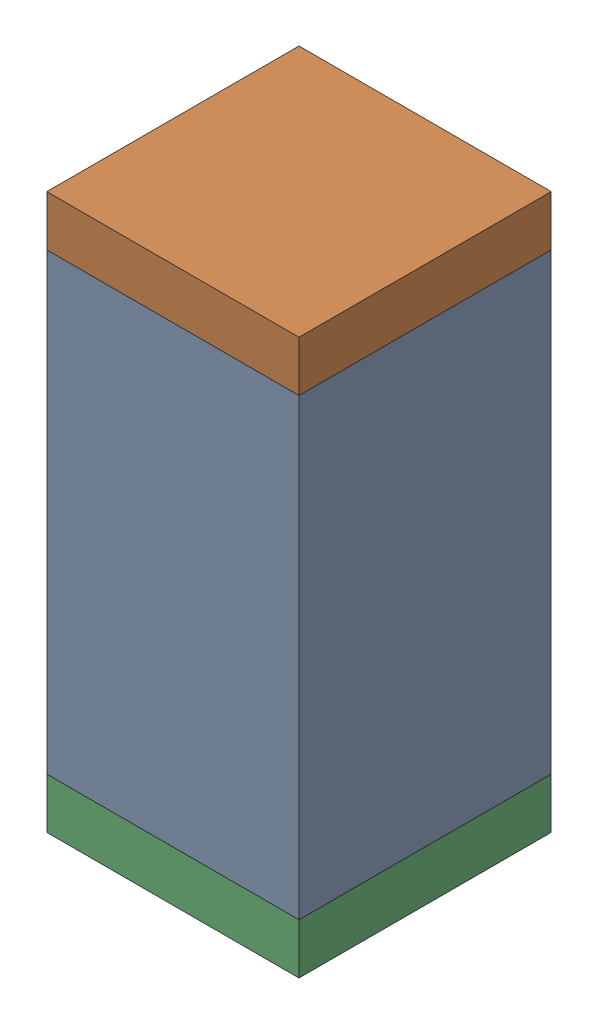
SolidWorks assembly C16, configuration Default. Lengths in mm.
Overall size (0.5 1.1 0.5).
6 component instances, 2 part files, 0 mates.
Components (placement in the parent):
- 791586336-1: 791586336 [Default] at (113.05 14.15 0) size (0.5 0.9 0.5)
  - Extruded_8-1: Extruded_8 [Default] at origin size (0.5 0.9 0.5)
- 810157360-1: 810157360 [Default] at (113.05 14.65 0) size (0.5 0.1 0.5)
  - Extruded_9-1: Extruded_9 [Default] at origin size (0.5 0.1 0.5)
- 810157360-2: 810157360 [Default] at (113.05 13.65 0) size (0.5 0.1 0.5)
  - Extruded_9-1: Extruded_9 [Default] at origin size (0.5 0.1 0.5)
